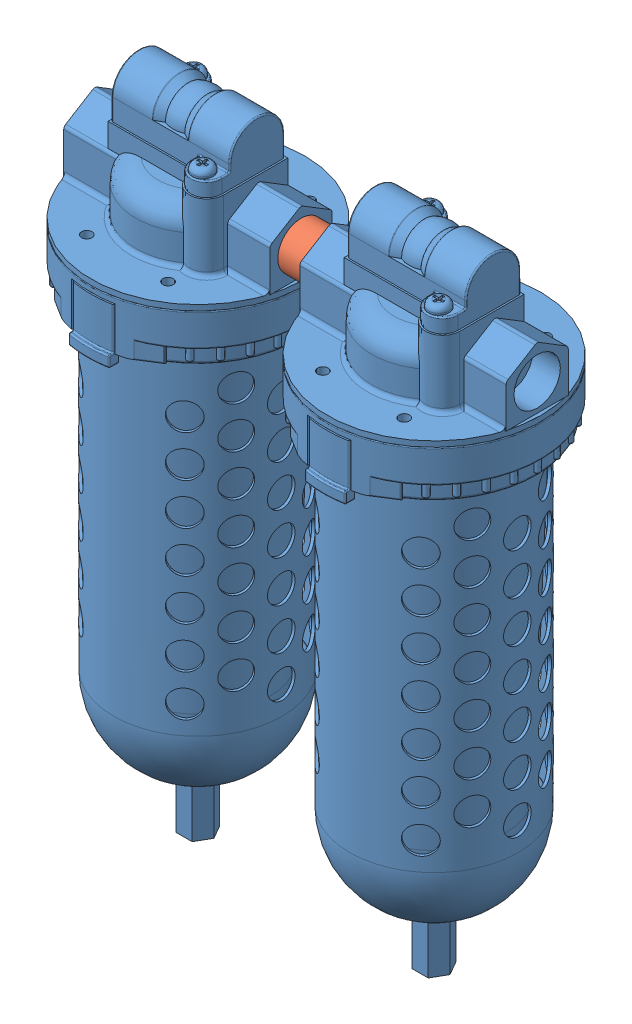
SolidWorks assembly ReadingTech_3P-060-P04-DCi, configuration Default. Lengths in mm.
Overall size (206.63 296.8 99.95).
3 component instances, 2 part files, 3 mates.
Components (placement in the parent):
- ReadingTech_3P060P04Fi-1: ReadingTech_3P060P04Fi [Default] at (-29.7933 -89.846 2.3172) size (98.17 296.8 99.95)
- ReadingTech_3P060P04Fi-2: ReadingTech_3P060P04Fi [Default] at (78.6647 -89.846 2.3172) size (98.17 296.8 99.95)
- ReadingTech- 60cfm_connector_.5in-1: ReadingTech- 60cfm_connector_.5in [Default] at (31.2937 126.054 2.3172) x (0 1 0) z (0 0 1) size (21.34 13.72 21.34)
Mates (geometry in assembly coordinates):
- Coincident1: coincident anti-aligned: circle of ReadingTech_3P060P04Fi-1; circle of ReadingTech- 60cfm_connector_.5in-1
- Coincident2: coincident aligned: circle of ReadingTech_3P060P04Fi-2; circle of ReadingTech- 60cfm_connector_.5in-1
- Coincident3: coincident aligned: plane of ReadingTech_3P060P04Fi-1 through (17.5777 113.354 16.6047) normal (0 0 1); plane of ReadingTech_3P060P04Fi-2 through (126.0357 113.354 16.6047) normal (0 0 1)
